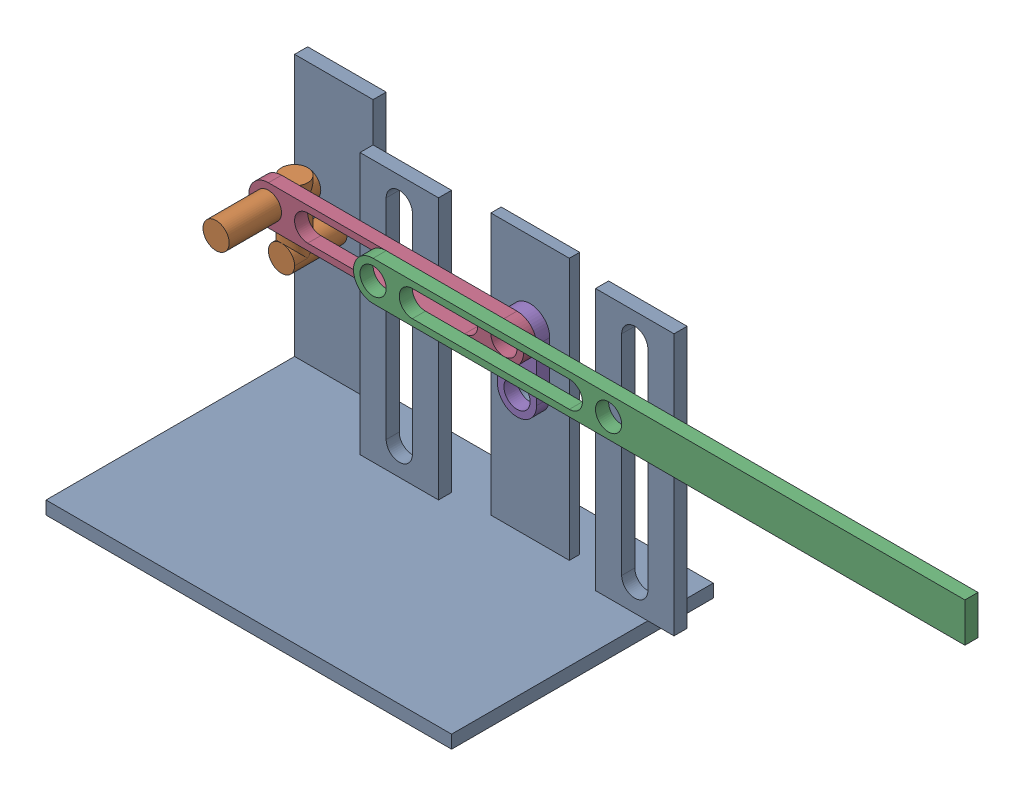
SolidWorks assembly Slide Assm 2, configuration Default. Lengths in mm.
Overall size (572.33 210 200).
5 component instances, 5 part files, 12 mates.
Components (placement in the parent):
- Base-1: Base [Default] at origin size (330 210 200)
- Crank-1: Crank [Default] at (30 110 -200) x (1 0 0) z (0 0 1) size (20 60 100)
- Arm-1: Arm [Default] at (120 150 -140) size (467.33 30 10)
- Crank Connect-1: Crank Connect [Default] at (30 150 -150) size (210 30 10)
- Internal Arm-1: Internal Arm [Default] at (210 150 -160) x (0 -1 0) z (0 0 1) size (70 30 10)
Mates (geometry in assembly coordinates):
- Coincident1: coordinate: point of Base-1
- Coincident2: coincident anti-aligned: line of Base-1 through (30 110 -200) axis (0 0 1); line of Crank-1 through (30 110 -150) axis (0 0 -1)
- Coincident3: coincident aligned: plane of Base-1 through (0 10 -200) normal (0 0 -1); plane of Crank-1 through (30 110 -200) normal (0 0 -1)
- Coincident4: coincident aligned: line of Crank-1 through (30 150 -100) axis (0 0 -1); line of Crank Connect-1 through (30 150 -140) axis (0 0 -1)
- Tangent1: tangent anti-aligned: cylinder of Crank-1 through (30 160 -160) axis (0 -1 0) radius 10; plane of Crank Connect-1 through (30 150 -150) normal (0 0 -1)
- Coincident5: coincident anti-aligned: line of Base-1 through (210 110 -167.9129) axis (0 0 1); line of Internal Arm-1 through (210 110 -150) axis (0 0 -1)
- Coincident6: coincident aligned: line of Crank Connect-1 through (210 150 -140) axis (0 0 -1); line of Internal Arm-1 through (210 150 -150) axis (0 0 -1)
- Coincident7: coincident anti-aligned: plane of Base-1 through (180 210 -160) normal (0 0 1); plane of Internal Arm-1 through (210 150 -160) normal (0 0 -1)
- Slot6: slot anti-aligned: cylinder of Arm-1 through (120 150 -130) axis (0 0 -1) radius 10; plane of Base-1 through (130 30 -350) normal (-1 0 0); cylinder of Base-1 through (120 30 -350) axis (0 0 1) radius 10
- Slot7: slot anti-aligned: cylinder of Arm-1 through (300 150 -130) axis (0 0 -1) radius 10; plane of Base-1 through (310 30 -350) normal (-1 0 0); cylinder of Base-1 through (300 30 -350) axis (0 0 1) radius 10
- Coincident8: coincident anti-aligned: plane of Arm-1 through (120 150 -140) normal (0 0 -1); plane of Crank Connect-1 through (30 150 -140) normal (0 0 1)
- Slot9: slot aligned: cylinder of Internal Arm-1 through (210 150 -150) axis (0 0 -1) radius 10; plane of Arm-1 through (150 140 -130) normal (0 1 0); cylinder of ? through (150 150 -130) axis (0 0 -1) radius 10
